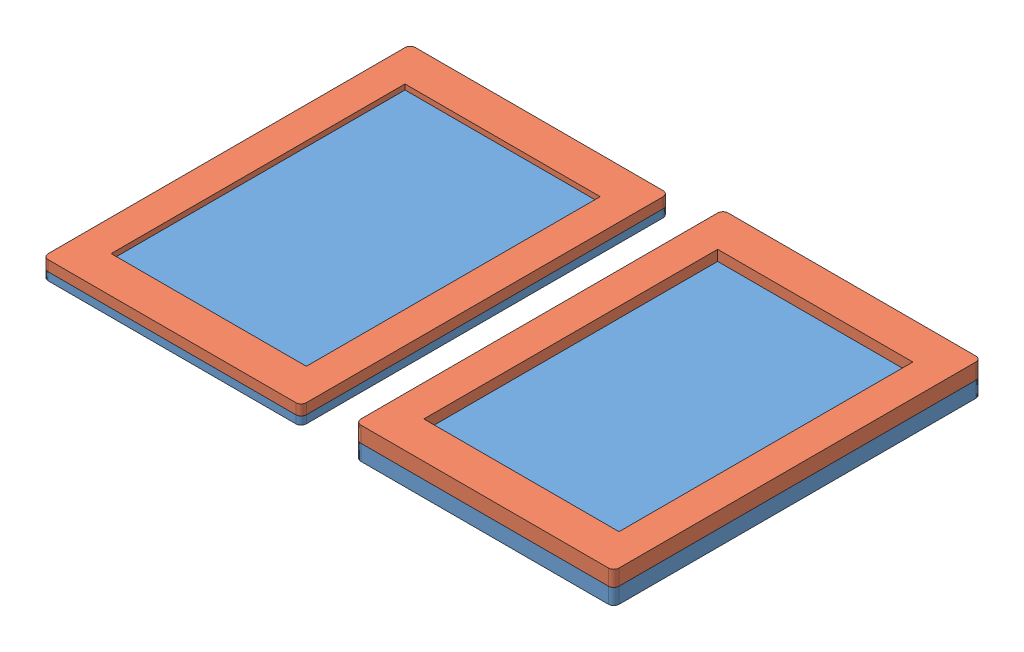
SolidWorks assembly InstaxFrameAssembly, configuration Default. Lengths in mm.
Overall size (138.16 7.62 88.9).
4 component instances, 2 part files, 15 mates.
Components (placement in the parent):
- BaseRevD-1: BaseRevD [Default] at (-21.2693 74.0105 46.2434) size (62.48 4.04 88.9)
- BaseRevD-2: BaseRevD [Slim] at (-96.9409 74.0105 46.2434) size (62.48 2.07 88.9)
- CoverC-2: CoverC [Slim] at (-96.4329 78.4555 46.2434) x (-1 0 0) z (0 0 1) size (62.48 3.81 88.9)
- CoverC-3: CoverC [Default] at (-20.7613 81.6305 46.2434) x (-1 0 0) z (0 0 1) size (62.48 6.35 88.9)
Mates (geometry in assembly coordinates):
- Coincident4: coincident anti-aligned: plane of Base-1 through (56.8164 49.0433 56.5557) normal (0 1 0); plane of Cover-1 through (57.3244 49.0433 56.5557) normal (0 -1 0)
- Coincident5: coincident aligned: plane of Base-1 through (56.8164 49.0433 102.6567) normal (0 0 1); plane of Cover-1 through (57.3244 50.3133 102.6567) normal (0 0 1)
- Coincident6: coincident aligned: plane of Base-1 through (88.3124 49.0433 56.5557) normal (1 0 0); plane of Cover-1 through (88.3124 50.3133 56.5557) normal (1 0 0)
- Coincident7: coincident aligned: plane of BaseRevD-1 through (-52.2573 77.8205 46.2434) normal (-1 0 0); plane of CoverC-1 through (-52.2573 79.0905 49.5454) normal (-1 0 0)
- Coincident8: coincident aligned: plane of BaseRevD-1 through (-21.2693 77.8205 92.3444) normal (0 0 1); plane of CoverC-1 through (-21.2693 79.0905 92.3444) normal (0 0 1)
- Coincident9: coincident anti-aligned: plane of BaseRevD-1 through (-21.2693 77.8205 46.2434) normal (0 1 0); plane of CoverC-1 through (-21.2693 77.8205 49.5454) normal (0 -1 0)
- Coincident10: coincident anti-aligned: plane of BaseRevD-1 through (-21.2693 77.8205 46.2434) normal (0 1 0); plane of CoverC-3 through (-20.7613 77.8205 46.2434) normal (0 -1 0)
- Coincident13: coincident aligned: plane of BaseRevD-1 through (10.2267 77.8205 46.2434) normal (1 0 0); plane of CoverC-3 through (10.2267 79.0905 46.2434) normal (1 0 0)
- Coincident14: coincident aligned: plane of BaseRevD-2 through (-65.4449 75.9155 46.2434) normal (1 0 0); plane of CoverC-2 through (-65.4449 77.1855 46.2434) normal (1 0 0)
- Coincident15: coincident aligned: plane of BaseRevD-2 through (-96.9409 75.9155 92.3444) normal (0 0 1); plane of CoverC-2 through (-96.4329 77.1855 92.3444) normal (0 0 1)
- Coincident16: coincident aligned: plane of BaseRevD-1 through (-21.2693 77.8205 92.3444) normal (0 0 1); plane of CoverC-3 through (-20.7613 79.0905 92.3444) normal (0 0 1)
- Parallel1: parallel aligned: plane of BaseRevD-1 through (-21.2693 77.8205 92.3444) normal (0 0 1); plane of BaseRevD-2 through (-96.9409 75.9155 92.3444) normal (0 0 1)
- Coincident21: coincident anti-aligned: plane of BaseRevD-2 through (-96.9409 75.9155 46.2434) normal (0 1 0); plane of CoverC-2 through (-96.4329 75.9155 46.2434) normal (0 -1 0)
- Coincident22: coincident aligned: plane of BaseRevD-1 through (-21.2693 74.0105 46.2434) normal (0 -1 0); plane of BaseRevD-2 through (-96.9409 74.0105 46.2434) normal (0 -1 0)
- Coincident23: coincident aligned: plane of CoverC-2 through (-96.4329 77.1855 92.3444) normal (0 0 1); plane of CoverC-3 through (-20.7613 79.0905 92.3444) normal (0 0 1)
